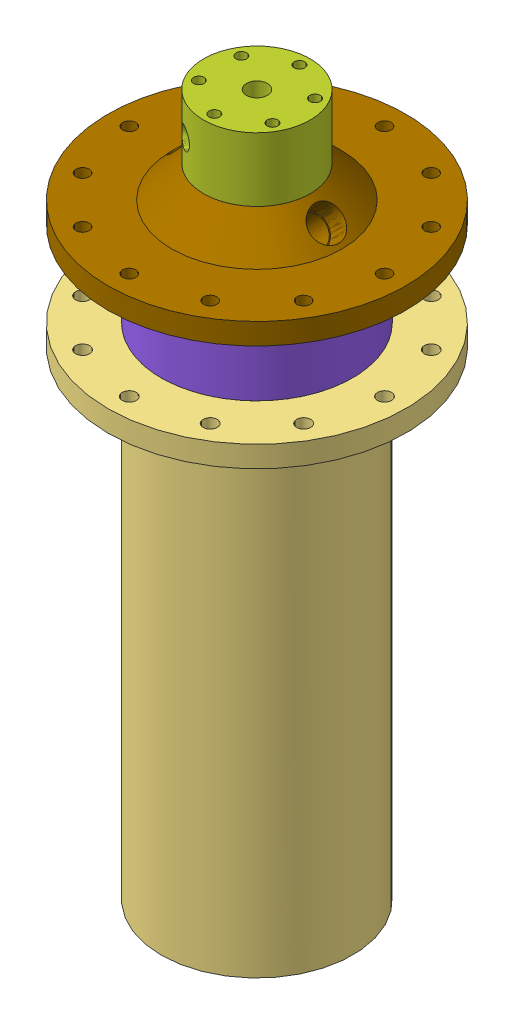
SolidWorks assembly APL1_firstEngineTest4, configuration config 2. Lengths in mm.
Overall size (177.8 419.1 177.8).
12 component instances, 12 part files, 28 mates.
Components (placement in the parent):
- APL1_ablativeInsert-1: APL1_ablativeInsert [Default] at (0 -6.35 0) x (0.930577 0 -0.366097) z (0.366097 0 0.930577)
- APL1_graphiteInsert-1: APL1_graphiteInsert [Default] at (0 -158.75 0) x (0.995497 0 -0.094792) z (0.094792 0 0.995497)
- APL1_OuterChamberCasing4-1: APL1_OuterChamberCasing4 [Default] at origin size (177.8 298.45 177.8)
- APL1_LowerInjectorPlate4-1: APL1_LowerInjectorPlate4 [Default] at (0 -6.35 0) x (-1 0 0) z (0 0 -1) size (114.3 6.35 114.3)
- APL1_TopInjectorPlate4-1: APL1_TopInjectorPlate4 [Default] x (-1 0 0) z (0 0 -1) size (88.9 19.05 88.9)
- APL1_LOXManifold4-1: APL1_LOXManifold4 [Default] at (0 38.1 0) size (88.9 33.34 88.9)
- APL1_ignitor4-1: APL1_ignitor4 [Default] at (0 88.9 0) x (0.5 0 -0.866025) z (0.866025 0 0.5) size (63.5 38.1 63.5)
- APL1_OuterManifold4-2: APL1_OuterManifold4 [Default] x (0.780737 0 0.624859) z (-0.624859 0 0.780737) size (114.3 50.8 114.3)
- APL1_dome4-1: APL1_dome4 [Default] at (0 50.8 0) x (-1 0 0) z (0 0 -1) size (177.8 31.75 177.8)
- APL1_ignitorCore4-1: APL1_ignitorCore4 [Default] at (0 -3.81 0) x (0.88212 0 0.471024) z (-0.471024 0 0.88212) size (25.4 95.25 25.4)
- APL1_Dowel4_1-1: APL1_Dowel4_1 [Default] at (41.275 -3.175 0) x (0.998297 0 0.058336) z (-0.058336 0 0.998297) size (3.17 25.4 3.17)
- APL1_dowel4_2-1: APL1_dowel4_2 [Default] at (35.7452 31.75 -20.6375) x (-0.66318 0 0.74846) z (-0.74846 0 -0.66318) size (3.17 22.23 3.17)
Mates (geometry in assembly coordinates):
- Coincident7: coincident anti-aligned: plane of APL1_ablativeInsert-1 through (-35.455 -158.75 13.9483) normal (0 -1 0); plane of APL1_graphiteInsert-1 through (-44.5786 -158.75 4.2448) normal (0 1 0)
- Coincident8: coordinate: point of APL1_OuterChamberCasing4-1
- Concentric1: concentric aligned: cylinder of APL1_ablativeInsert-1 through (0 -6.35 0) axis (0 1 0) radius 51.1302; cylinder of APL1_OuterChamberCasing4-1 through (0 0 0) axis (0 1 0) radius 57.15
- Concentric2: concentric aligned: cylinder of APL1_graphiteInsert-1 through (0 -158.75 0) axis (0 1 0) radius 51.1302; cylinder of APL1_OuterChamberCasing4-1 through (0 0 0) axis (0 1 0) radius 57.15
- Concentric4: concentric anti-aligned: cylinder of APL1_OuterChamberCasing4-1 through (0 0 0) axis (0 1 0) radius 57.15; cylinder of APL1_LowerInjectorPlate4-1 through (0 -6.35 0) axis (0 -1 0) radius 57.15
- Concentric6: concentric anti-aligned: cylinder of APL1_OuterChamberCasing4-1 through (0 0 0) axis (0 1 0) radius 88.9; cylinder of APL1_TopInjectorPlate4-1 through (0 0 0) axis (0 -1 0) radius 44.45
- Coincident11: coincident anti-aligned: plane of APL1_LowerInjectorPlate4-1 through (57.15 0 0) normal (0 1 0); plane of APL1_TopInjectorPlate4-1 through (10.9855 0 0) normal (0 -1 0)
- Concentric7: concentric anti-aligned: cylinder of APL1_OuterChamberCasing4-1 through (0 0 0) axis (0 1 0) radius 57.15; cylinder of APL1_LOXManifold4-1 through (0 38.1 0) axis (0 -1 0) radius 44.45
- Coincident12: coincident anti-aligned: plane of APL1_TopInjectorPlate4-1 through (31.75 17.4625 0) normal (0 1 0); plane of APL1_LOXManifold4-1 through (-44.45 17.4625 0) normal (0 -1 0)
- Coincident14: coincident anti-aligned: plane of APL1_ablativeInsert-1 through (-35.455 -6.35 13.9483) normal (0 1 0); plane of APL1_LowerInjectorPlate4-1 through (6.35 -6.35 0) normal (0 -1 0)
- Concentric9: concentric anti-aligned: cylinder of APL1_OuterChamberCasing4-1 through (0 0 0) axis (0 1 0) radius 57.15; cylinder of APL1_OuterManifold4-2 through (0 0 0) axis (0 -1 0) radius 57.15
- Coincident15: coincident anti-aligned: plane of APL1_LowerInjectorPlate4-1 through (57.15 0 0) normal (0 1 0); plane of APL1_OuterManifold4-2 through (-44.6191 0 -35.7107) normal (0 -1 0)
- Concentric10: concentric anti-aligned: cylinder of APL1_OuterChamberCasing4-1 through (0 0 0) axis (0 1 0) radius 57.15; cylinder of APL1_ignitor4-1 through (0 88.9 0) axis (0 -1 0) radius 31.75
- Coincident17: coincident anti-aligned: plane of APL1_OuterChamberCasing4-1 through (-51.1302 -6.35 0) normal (0 1 0); plane of APL1_LowerInjectorPlate4-1 through (6.35 -6.35 0) normal (0 -1 0)
- Concentric11: concentric anti-aligned: cylinder of APL1_OuterChamberCasing4-1 through (0 0 0) axis (0 1 0) radius 57.15; cylinder of APL1_dome4-1 through (0 50.8 0) axis (0 -1 0) radius 88.9
- Coincident18: coincident anti-aligned: plane of APL1_LOXManifold4-1 through (-14.2875 50.8 0) normal (0 1 0); plane of APL1_dome4-1 through (6.35 50.8 0) normal (0 -1 0)
- Concentric13: concentric anti-aligned: cylinder of APL1_OuterChamberCasing4-1 through (0 0 0) axis (0 1 0) radius 57.15; cylinder of APL1_ignitorCore4-1 through (0 -3.81 0) axis (0 -1 0) radius 6.35
- Coincident22: coincident anti-aligned: plane of APL1_ignitorCore4-1 through (-9.6905 82.55 -5.1744) normal (0 -1 0); plane of APL1_dome4-1 through (31.75 82.55 0) normal (0 1 0)
- Coincident23: coincident anti-aligned: plane of APL1_ignitor4-1 through (-1.905 88.9 3.2996) normal (0 -1 0); plane of APL1_ignitorCore4-1 through (-11.2029 88.9 -5.982) normal (0 1 0)
- Concentric15: concentric aligned: cylinder of APL1_ignitor4-1 through (-21.997 120.65 12.7) axis (0 1 0) radius 3.175; cylinder of APL1_dome4-1 through (-21.997 82.55 12.7) axis (0 1 0) radius 2.5527
- Concentric16: concentric anti-aligned: cylinder of APL1_TopInjectorPlate4-1 through (41.275 17.4625 0) axis (0 1 0) radius 1.5875; cylinder of APL1_LOXManifold4-1 through (41.275 17.4625 0) axis (0 -1 0) radius 1.5875
- Concentric17: concentric aligned: cylinder of APL1_LowerInjectorPlate4-1 through (41.275 0 0) axis (0 1 0) radius 1.5875; cylinder of APL1_TopInjectorPlate4-1 through (41.275 17.4625 0) axis (0 1 0) radius 1.5875
- Concentric18: concentric anti-aligned: cylinder of APL1_TopInjectorPlate4-1 through (41.275 17.4625 0) axis (0 1 0) radius 1.5875; cylinder of APL1_Dowel4_1-1 through (41.275 22.225 0) axis (0 -1 0) radius 1.5875
- Coincident24: coincident anti-aligned: circle of APL1_LowerInjectorPlate4-1; plane of APL1_Dowel4_1-1 through (41.275 -3.175 0) normal (0 -1 0)
- Concentric19: concentric aligned: cylinder of APL1_OuterChamberCasing4-1 through (-76.2 0 0) axis (0 1 0) radius 4.2164; cylinder of APL1_dome4-1 through (-76.2 63.5 0) axis (0 1 0) radius 3.9688
- Concentric24: concentric aligned: cylinder of APL1_dome4-1 through (35.7452 50.8 -20.6375) axis (0 -1 0) radius 1.5875; cylinder of APL1_dowel4_2-1 through (35.7452 53.975 -20.6375) axis (0 -1 0) radius 1.5875
- Concentric29: concentric anti-aligned: cylinder of APL1_LOXManifold4-1 through (35.7452 38.1 -20.6375) axis (0 1 0) radius 1.5875; cylinder of APL1_dowel4_2-1 through (35.7452 53.975 -20.6375) axis (0 -1 0) radius 1.5875
- Coincident25: coincident anti-aligned: circle of APL1_dome4-1; plane of APL1_dowel4_2-1 through (35.7452 53.975 -20.6375) normal (0 1 0)
